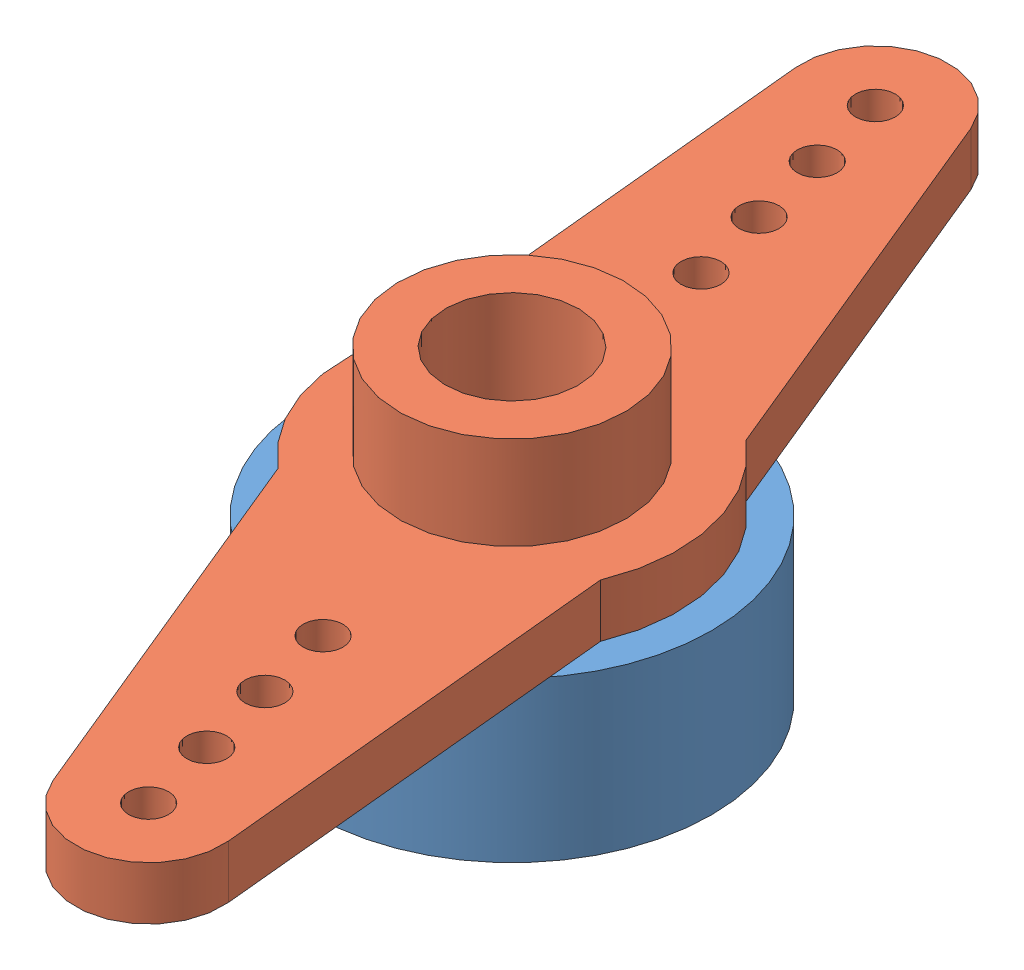
SolidWorks assembly Turning Servo Adapter, configuration Default. Lengths in mm.
Overall size (22.51 11.85 44.75).
2 component instances, 2 part files, 3 mates.
Components (placement in the parent):
- Servo Adapter-1: Servo Adapter [Default] at origin size (15 6.35 15)
- Servo Horn-1: Servo Horn [Default] at (0 6 0) x (0.970404 0 -0.241488) z (0 1 0) size (12.5 43 5.5)
Mates (geometry in assembly coordinates):
- Coincident1: coordinate: point of Servo Adapter-1
- Coincident2: coincident anti-aligned: plane of Servo Adapter-1 through (0 6 0) normal (0 1 0); plane of Servo Horn-1 through (0 6 0) normal (0 -1 0)
- Concentric1: concentric aligned: cylinder of Servo Adapter-1 through (0 6 0) axis (0 -1 0) radius 7.5; cylinder of Servo Horn-1 through (0 8 0) axis (0 -1 0) radius 2.5
